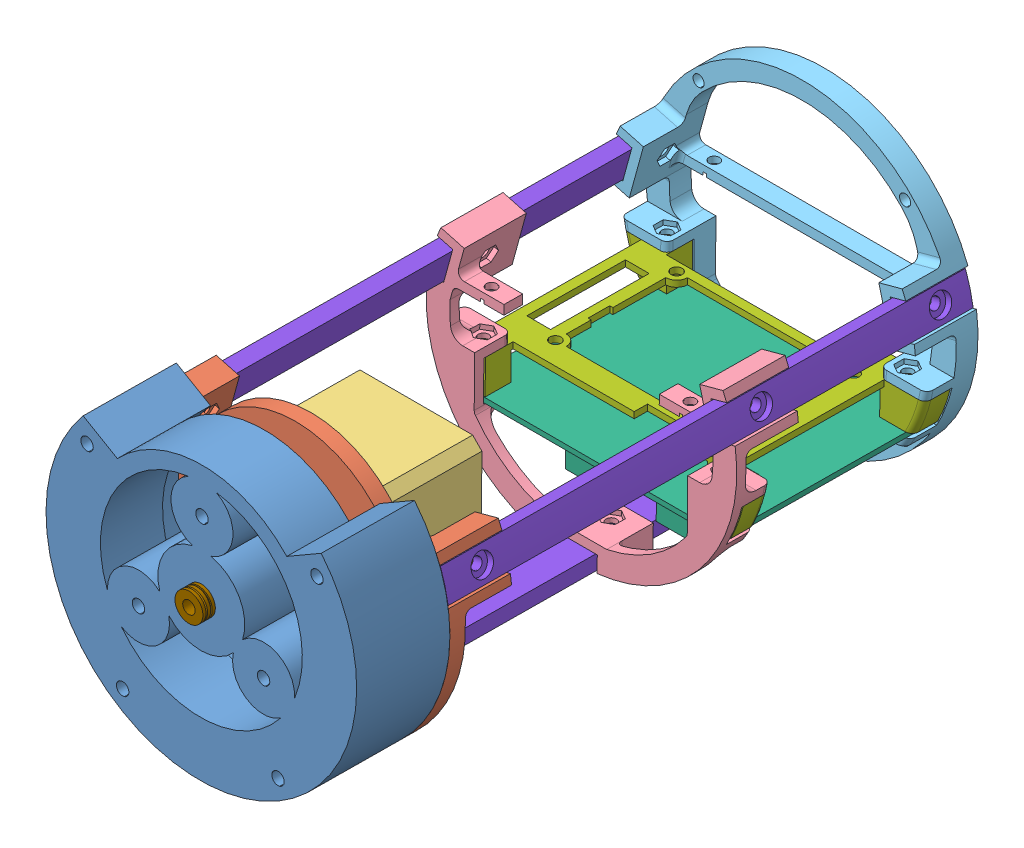
SolidWorks assembly Control cabin, configuration 默认. Lengths in mm.
Overall size (100 99.87 204.47).
11 component instances, 9 part files, 23 mates.
Components (placement in the parent):
- parts_rough-2: parts_rough [默认] at (99.171 -9.6682 20.1029) x (-1 0 0) z (0 0.999962 -0.008727) size (100 30 87.5)
- Roll_motor_mount-1: Roll_motor_mount [默认] at (999.171 -309.9186 -7.278) x (-1 0 0) z (0 -0.008727 -0.999962) size (100 84.7 20)
- motors_17_42_34mm-1: motors_17_42_34mm [默认] at (19.171 -10.2267 -43.8947) x (1 0 0) z (0 0.008727 0.999962) size (42.3 42.3 58)
- Circuit_rack_end-1: Circuit_rack_end [默认] at (849.171 -310.7243 -99.5995) x (-1 0 0) z (0 -0.008727 -0.999962) size (100 70.66 20)
- Circuit_rack_endcap_mount-1: Circuit_rack_endcap_mount [默认] at (-350.829 -311.4021 -177.2715) x (1 0 0) z (0 0.008727 0.999962) size (100 99.7 20)
- Control_board-1: Control_board [默认] at (141.716 -33.1654 -105.5219) x (-1 0 0) z (0 -0.999962 0.008727) size (85.09 66.67 20.6)
- Fathom-S_mounting_bracket-1: Fathom-S_mounting_bracket [默认] at (849.171 -22.2567 -138.9558) x (-1 0 0) z (0 -0.999962 0.008727) size (97.61 66.67 11)
- Chassis_beam_PCB_mount-1: Chassis_beam_PCB_mount [默认] at (-137.7847 1054.984 -19.6894) x (0.258819 -0.965889 0.008429) z (0.965926 0.258809 -0.002259) size (10 169 5)
- Chassis_beam_PCB_mount-2: Chassis_beam_PCB_mount [默认] at (1189.171 -56.6826 -9.988) x (-1 0 0) z (0 -0.999962 0.008727) size (10 169 5)
- Chassis_beam_PCB_mount-3: Chassis_beam_PCB_mount [默认] at (-228.0988 -1050.6541 -1.3137) x (0.258819 0.965889 -0.008429) z (-0.965926 0.258809 -0.002259) size (10 169 5)
- F4-9M-1: F4-9M [默认] at (189.171 -9.6333 24.1027) x (1 0 0) z (0 0.999962 -0.008727) size (9 4 9)
Mates (geometry in assembly coordinates):
- 同心1: concentric anti-aligned: cylinder of parts_rough-2 through (99.171 -9.6682 20.1029) axis (0 -0.008727 -0.999962) radius 50; cylinder of Roll_motor_mount-1 through (99.171 -9.9737 -14.8958) axis (0 0.008727 0.999962) radius 50
- 重合1: coincident anti-aligned: plane of parts_rough-2 through (99.171 -9.93 -9.896) normal (0 -0.008727 -0.999962); plane of Roll_motor_mount-1 through (99.171 -9.93 -9.896) normal (0 0.008727 0.999962)
- 同心2: concentric anti-aligned: cylinder of Roll_motor_mount-1 through (99.171 -9.93 -9.896) axis (0 0.008727 0.999962) radius 11.5; cylinder of motors_17_42_34mm-1 through (99.171 -9.7642 9.1033) axis (0 -0.008727 -0.999962) radius 11
- 平行1: parallel aligned: cylinder of Roll_motor_mount-1 through (89.2715 -0.0309 -9.9824) axis (0 0.008727 0.999962) radius 1.7; cylinder of motors_17_42_34mm-1 through (83.671 5.5257 -15.0311) axis (0 0.008727 0.999962) radius 1.5
- 重合2: coincident anti-aligned: plane of Roll_motor_mount-1 through (49.171 -9.9737 -14.8958) normal (0 -0.008727 -0.999962); plane of motors_17_42_34mm-1 through (19.171 -9.9737 -14.8958) normal (0 0.008727 0.999962)
- 同心4: concentric anti-aligned: cylinder of parts_rough-2 through (99.171 -9.6682 20.1029) axis (0 -0.008727 -0.999962) radius 50; cylinder of Circuit_rack_end-1 through (99.171 -10.7619 -105.2174) axis (0 0.008727 0.999962) radius 50
- 同心5: concentric anti-aligned: cylinder of Circuit_rack_end-1 through (99.171 -10.7619 -105.2174) axis (0 0.008727 0.999962) radius 50; cylinder of Circuit_rack_endcap_mount-1 through (99.171 -11.3406 -171.5311) axis (0 -0.008727 -0.999962) radius 50
- 同心7: concentric anti-aligned: cylinder of Circuit_rack_end-1 through (137.906 -37.7985 -109.2916) axis (0 -0.999962 0.008727) radius 1.7; cylinder of Control_board-1 through (137.906 -33.1986 -109.3317) axis (0 0.999962 -0.008727) radius 1.5
- 同心8: concentric anti-aligned: cylinder of Circuit_rack_end-1 through (60.436 -37.7985 -109.2916) axis (0 -0.999962 0.008727) radius 1.7; cylinder of Control_board-1 through (60.436 -33.1986 -109.3317) axis (0 0.999962 -0.008727) radius 1.5
- 同心9: concentric anti-aligned: cylinder of Circuit_rack_endcap_mount-1 through (60.436 -38.3138 -168.3443) axis (0 -0.999962 0.008727) radius 1.7; cylinder of Control_board-1 through (60.436 -33.714 -168.3845) axis (0 0.999962 -0.008727) radius 1.5
- 同心10: concentric anti-aligned: cylinder of Circuit_rack_endcap_mount-1 through (137.906 -38.3138 -168.3443) axis (0 -0.999962 0.008727) radius 1.7; cylinder of Control_board-1 through (137.906 -33.714 -168.3845) axis (0 0.999962 -0.008727) radius 1.5
- 重合3: coincident anti-aligned: plane of Circuit_rack_endcap_mount-1 through (149.172 -35.3515 -172.6803) normal (0 0.999962 -0.008727); plane of Control_board-1 through (141.716 -34.7653 -105.5079) normal (0 -0.999962 0.008727)
- 同心11: concentric anti-aligned: cylinder of Circuit_rack_end-1 through (137.906 -21.9991 -109.4294) axis (0 -0.999962 0.008727) radius 1.7; cylinder of Fathom-S_mounting_bracket-1 through (137.906 -21.9991 -109.4294) axis (0 0.999962 -0.008727) radius 1.8
- 同心12: concentric anti-aligned: cylinder of Circuit_rack_endcap_mount-1 through (137.906 -22.5144 -168.4822) axis (0 -0.999962 0.008727) radius 1.7; cylinder of Fathom-S_mounting_bracket-1 through (137.906 -22.5144 -168.4822) axis (0 0.999962 -0.008727) radius 1.8
- 重合4: coincident anti-aligned: plane of Circuit_rack_endcap_mount-1 through (149.172 -22.4756 -164.0374) normal (0 -0.999962 0.008727); plane of Fathom-S_mounting_bracket-1 through (147.8541 -22.5477 -172.2921) normal (0 0.999962 -0.008727)
- 同心13: concentric anti-aligned: cylinder of Circuit_rack_end-1 through (140.7058 0.3058 -112.3142) axis (-0.965926 -0.258809 0.002259) radius 1.7; circle of Chassis_beam_PCB_mount-1
- 重合7: coincident anti-aligned: plane of Circuit_rack_end-1 through (143.5782 -4.5311 -102.2716) normal (0.965926 0.258809 -0.002259); plane of Chassis_beam_PCB_mount-1 through (143.4488 -3.2468 -10.4543) normal (-0.965926 -0.258809 0.002259)
- 平行3: parallel anti-aligned: cylinder of Roll_motor_mount-1 through (140.7058 1.0897 -22.4926) axis (-0.965926 -0.258809 0.002259) radius 1.7; cylinder of Chassis_beam_PCB_mount-1 through (146.9844 2.7719 -22.5073) axis (0.965926 0.258809 -0.002259) radius 1.8
- 同心15: concentric aligned: cylinder of Circuit_rack_endcap_mount-1 through (140.7058 -0.1975 -169.987) axis (-0.965926 -0.258809 0.002259) radius 1.7; cylinder of Chassis_beam_PCB_mount-1 through (142.1547 0.1907 -169.9904) axis (-0.965926 -0.258809 0.002259) radius 1.8
- 同心16: concentric anti-aligned: cylinder of Roll_motor_mount-1 through (140.7058 1.0897 -22.4926) axis (-0.965926 -0.258809 0.002259) radius 1.7; cylinder of Chassis_beam_PCB_mount-1 through (146.9844 2.7719 -22.5073) axis (0.965926 0.258809 -0.002259) radius 1.8
- 同心17: concentric aligned: cylinder of Circuit_rack_endcap_mount-1 through (140.7058 -0.1975 -169.987) axis (-0.965926 -0.258809 0.002259) radius 1.7; cylinder of Chassis_beam_PCB_mount-1 through (142.1547 0.1907 -169.9904) axis (-0.965926 -0.258809 0.002259) radius 1.8
- 同心18: concentric aligned: cylinder of parts_rough-2 through (99.171 -9.6682 20.1029) axis (0 0.008727 0.999962) radius 2.5; cylinder of F4-9M-1 through (99.171 -9.6682 20.1029) axis (0 0.008727 0.999962) radius 2
- 重合8: coincident anti-aligned: plane of parts_rough-2 through (99.171 -9.6682 20.1029) normal (0 0.008727 0.999962); plane of F4-9M-1 through (103.671 -9.6682 20.1029) normal (0 -0.008727 -0.999962)
